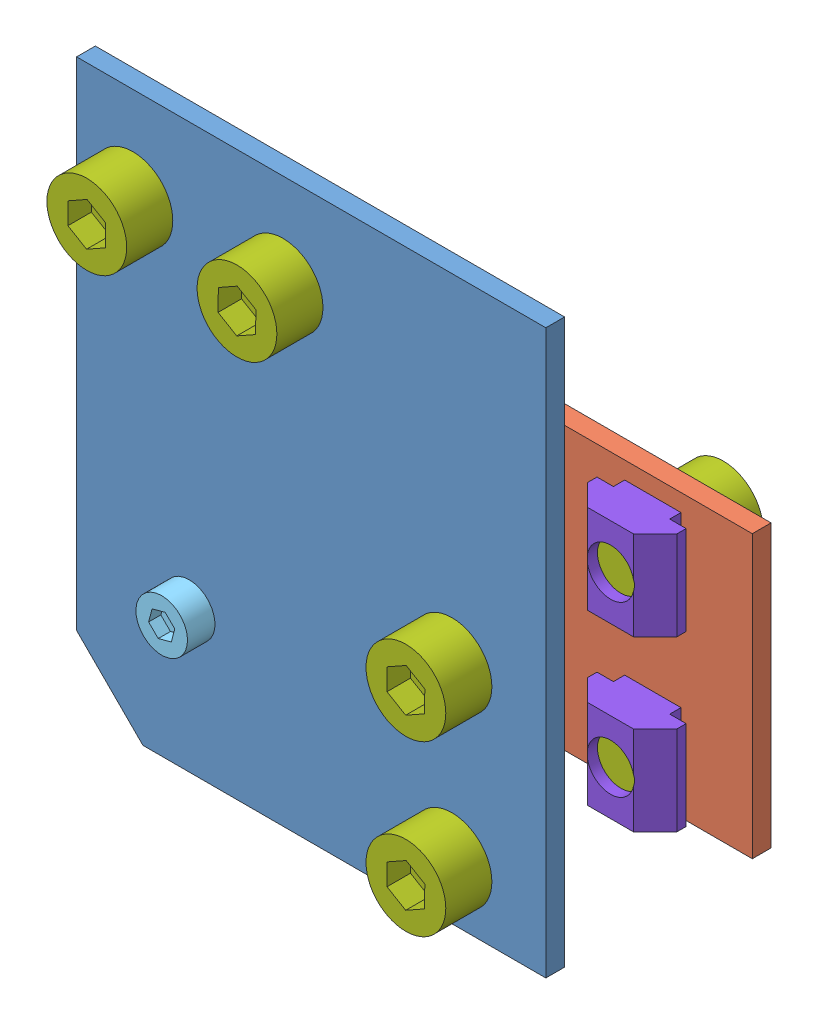
SolidWorks assembly 051XY惰轮组合1, configuration 默认. Lengths in mm.
Overall size (50 60 34.91).
21 component instances, 8 part files, 42 mates.
Components (placement in the parent):
- XY惰轮上固定片-1: XY惰轮上固定片 [默认] at (-52.8313 -43.6236 78.5) x (1 0 0) z (0 -1 0) size (50 2 60)
- XY惰轮下固定片-1: XY惰轮下固定片 [默认] at (-52.8313 -43.6236 56.5) x (1 0 0) z (0 -1 0) size (50 2 30)
- M3_6_1尼龙垫片-1: M3_6_1尼龙垫片 [默认] at (-40.8313 -28.6236 58.5) x (1 0 0) z (0 -1 0) size (6 1 6)
- 2GT惰轮6MM20齿3MM孔-带齿-1: 2GT惰轮6MM20齿3MM孔-带齿 [默认] at (-40.8313 -28.6236 59.5) x (1 0 0) z (0 -1 0) size (18 8.5 18)
- M3_6_1尼龙垫片-2: M3_6_1尼龙垫片 [默认] at (-40.8313 -28.6236 68) x (1 0 0) z (0 -1 0) size (6 1 6)
- 2GT惰轮6MM20齿3MM孔-带齿-2: 2GT惰轮6MM20齿3MM孔-带齿 [默认] at (-40.8313 -28.6236 69) x (1 0 0) z (0 -1 0) size (18 8.5 18)
- M3_6_1尼龙垫片-3: M3_6_1尼龙垫片 [默认] at (-40.8313 -28.6236 77.5) x (1 0 0) z (0 -1 0) size (6 1 6)
- M3_30-1: M3_30 [默认] at (-40.8313 -28.6236 50.5) x (1 0 0) z (0 -1 0) size (5.5 32.93 5.5)
- M3尼龙螺母-1: M3尼龙螺母 [默认] at (-40.8313 -28.6236 56.5) x (1 0 0) z (0 1 0) size (6.88 4 6.18)
- M5_6-1: M5_6 [默认] at (-12.8313 -37.6236 74.5) x (1 0 0) z (0 -1 0) size (8.5 10.91 8.5)
- M5_6-2: M5_6 [默认] at (-12.8313 -19.6236 74.5) x (1 0 0) z (0 -1 0) size (8.5 10.91 8.5)
- M5_6-3: M5_6 [默认] at (-46.8313 6.3764 74.5) x (1 0 0) z (0 -1 0) size (8.5 10.91 8.5)
- M5_6-4: M5_6 [默认] at (-30.8313 6.3764 74.5) x (1 0 0) z (0 -1 0) size (8.5 10.91 8.5)
- 欧标20M5滑块螺母-1: 欧标20M5滑块螺母 [默认] at (-51.5813 1.6264 73.4) x (1 0 0) z (0 -1 0) size (9.5 4.5 9.5)
- 欧标20M5滑块螺母-2: 欧标20M5滑块螺母 [默认] at (-35.5813 1.6264 73.4) x (1 0 0) z (0 -1 0) size (9.5 4.5 9.5)
- 欧标20M5滑块螺母-3: 欧标20M5滑块螺母 [默认] at (-8.0813 -24.3736 73.4) x (0 1 0) z (1 0 0) size (9.5 4.5 9.5)
- 欧标20M5滑块螺母-4: 欧标20M5滑块螺母 [默认] at (-8.0813 -42.3736 73.4) x (0 1 0) z (1 0 0) size (9.5 4.5 9.5)
- M5_6-5: M5_6 [默认] at (-12.8313 -19.6236 62.5) x (1 0 0) z (0 1 0) size (8.5 10.91 8.5)
- M5_6-6: M5_6 [默认] at (-12.8313 -37.6236 62.5) x (1 0 0) z (0 1 0) size (8.5 10.91 8.5)
- 欧标20M5滑块螺母-5: 欧标20M5滑块螺母 [默认] at (-17.5813 -24.3736 63.6) x (0 1 0) z (-1 0 0) size (9.5 4.5 9.5)
- 欧标20M5滑块螺母-6: 欧标20M5滑块螺母 [默认] at (-17.5813 -42.3736 63.6) x (0 1 0) z (-1 0 0) size (9.5 4.5 9.5)
Mates (geometry in assembly coordinates):
- 距离1: distance = 20 mm: plane of assembly; plane of assembly; plane of XY惰轮下固定片-1 through (-52.8313 -43.6236 58.5) normal (0 0 1); plane of XY惰轮上固定片-1 through (-52.8313 -43.6236 78.5) normal (0 0 -1)
- 同心2: concentric: circle of assembly; circle of assembly; circle of XY惰轮上固定片-1; circle of XY惰轮下固定片-1
- 重合1: coincident: plane of assembly; plane of assembly; plane of XY惰轮下固定片-1 through (-52.8313 -43.6236 58.5) normal (0 0 1); plane of M3_6_1尼龙垫片-1 through (-40.8313 -28.6236 58.5) normal (0 0 -1)
- 同心5: concentric: circle of assembly; circle of assembly; circle of XY惰轮下固定片-1; circle of M3_6_1尼龙垫片-1
- 重合2: coincident: plane of assembly; plane of assembly; plane of M3_6_1尼龙垫片-1 through (-40.8313 -28.6236 59.5) normal (0 0 1); plane of 2GT惰轮6MM20齿3MM孔-带齿-1 through (-40.8313 -28.6236 59.5) normal (0 0 -1)
- 同心6: concentric: circle of assembly; circle of assembly; circle of M3_6_1尼龙垫片-1; circle of 2GT惰轮6MM20齿3MM孔-带齿-1
- 重合3: coincident: plane of assembly; plane of assembly; plane of 2GT惰轮6MM20齿3MM孔-带齿-1 through (-40.8313 -28.6236 68) normal (0 0 1); plane of M3_6_1尼龙垫片-2 through (-40.8313 -28.6236 68) normal (0 0 -1)
- 同心7: concentric: circle of assembly; circle of assembly; circle of 2GT惰轮6MM20齿3MM孔-带齿-1; circle of M3_6_1尼龙垫片-2
- 重合4: coincident: plane of assembly; plane of assembly; plane of M3_6_1尼龙垫片-2 through (-40.8313 -28.6236 69) normal (0 0 1); plane of 2GT惰轮6MM20齿3MM孔-带齿-2 through (-40.8313 -28.6236 69) normal (0 0 -1)
- 同心8: concentric: circle of assembly; circle of assembly; circle of M3_6_1尼龙垫片-2; circle of 2GT惰轮6MM20齿3MM孔-带齿-2
- 重合5: coincident: plane of assembly; plane of assembly; plane of 2GT惰轮6MM20齿3MM孔-带齿-2 through (-40.8313 -28.6236 77.5) normal (0 0 1); plane of M3_6_1尼龙垫片-3 through (-40.8313 -28.6236 77.5) normal (0 0 -1)
- 同心9: concentric: circle of assembly; circle of assembly; circle of 2GT惰轮6MM20齿3MM孔-带齿-2; circle of M3_6_1尼龙垫片-3
- 同心10: concentric: cylinder of assembly; cylinder of assembly; cylinder of XY惰轮上固定片-1 through (-40.8313 -28.6236 78.5) axis (0 0 1) radius 1.75; cylinder of M3_30-1 through (-40.8313 -28.6236 80.5) axis (0 0 -1) radius 1.5
- 重合6: coincident: plane of assembly; plane of assembly; plane of XY惰轮上固定片-1 through (-52.8313 -43.6236 80.5) normal (0 0 1); plane of M3_30-1 through (-40.8313 -28.6236 80.5) normal (0 0 -1)
- 同心11: concentric: cylinder of assembly; cylinder of assembly; cylinder of M3_30-1 through (-40.8313 -28.6236 80.5) axis (0 0 -1) radius 1.5; cylinder of M3尼龙螺母-1 through (-40.8313 -28.6236 52.5) axis (0 0 1) radius 1.5
- 重合7: coincident: plane of assembly; plane of assembly; plane of XY惰轮下固定片-1 through (-52.8313 -43.6236 56.5) normal (0 0 -1); plane of M3尼龙螺母-1 through (-40.8313 -28.6236 56.5) normal (0 0 1)
- 重合8: coincident: plane of assembly; plane of assembly; plane of XY惰轮上固定片-1 through (-52.8313 -43.6236 80.5) normal (0 0 1); plane of M5_6-3 through (-46.8313 6.3764 80.5) normal (0 0 -1)
- 同心12: concentric: cylinder of assembly; cylinder of assembly; cylinder of XY惰轮上固定片-1 through (-46.8313 6.3764 78.5) axis (0 0 1) radius 2.75; cylinder of M5_6-3 through (-46.8313 6.3764 80.5) axis (0 0 -1) radius 2.5
- 同心13: concentric: cylinder of assembly; cylinder of assembly; cylinder of M5_6-3 through (-46.8313 6.3764 80.5) axis (0 0 -1) radius 2.5; cylinder of 欧标20M5滑块螺母-1 through (-46.8313 6.3764 73.4) axis (0 0 1) radius 2.5
- 距离2: distance = 1.8 mm: plane of assembly; plane of assembly; plane of XY惰轮上固定片-1 through (-52.8313 -43.6236 78.5) normal (0 0 -1); plane of 欧标20M5滑块螺母-1 through (-51.5813 1.6264 76.7) normal (0 0 1)
- 重合9: coincident: plane of assembly; plane of assembly; plane of XY惰轮上固定片-1 through (-52.8313 -43.6236 80.5) normal (0 0 1); plane of M5_6-4 through (-30.8313 6.3764 80.5) normal (0 0 -1)
- 同心14: concentric: cylinder of assembly; cylinder of assembly; cylinder of XY惰轮上固定片-1 through (-30.8313 6.3764 78.5) axis (0 0 1) radius 2.75; cylinder of M5_6-4 through (-30.8313 6.3764 80.5) axis (0 0 -1) radius 2.5
- 同心15: concentric: cylinder of assembly; cylinder of assembly; cylinder of M5_6-4 through (-30.8313 6.3764 80.5) axis (0 0 -1) radius 2.5; cylinder of 欧标20M5滑块螺母-2 through (-30.8313 6.3764 73.4) axis (0 0 1) radius 2.5
- 距离3: distance = 1.8 mm: plane of assembly; plane of assembly; plane of XY惰轮上固定片-1 through (-52.8313 -43.6236 78.5) normal (0 0 -1); plane of 欧标20M5滑块螺母-2 through (-35.5813 1.6264 76.7) normal (0 0 1)
- 重合10: coincident: plane of assembly; plane of assembly; plane of XY惰轮上固定片-1 through (-52.8313 -43.6236 80.5) normal (0 0 1); plane of M5_6-2 through (-12.8313 -19.6236 80.5) normal (0 0 -1)
- 同心16: concentric: cylinder of assembly; cylinder of assembly; cylinder of XY惰轮上固定片-1 through (-12.8313 -19.6236 78.5) axis (0 0 1) radius 2.75; cylinder of M5_6-2 through (-12.8313 -19.6236 80.5) axis (0 0 -1) radius 2.5
- 同心17: concentric: cylinder of assembly; cylinder of assembly; cylinder of M5_6-2 through (-12.8313 -19.6236 80.5) axis (0 0 -1) radius 2.5; cylinder of 欧标20M5滑块螺母-3 through (-12.8313 -19.6236 73.4) axis (0 0 1) radius 2.5
- 距离4: distance = 1.8 mm: plane of XY惰轮上固定片-1 through (-52.8313 -43.6236 78.5) normal (0 0 -1); plane of 欧标20M5滑块螺母-3 through (-8.0813 -24.3736 76.7) normal (0 0 1)
- 平行1: parallel: plane of XY惰轮上固定片-1 through (-2.8313 -43.6236 80.5) normal (1 0 0); plane of 欧标20M5滑块螺母-3 through (-17.5813 -14.8736 76.7) normal (-1 0 0)
- 重合11: coincident: plane of assembly; plane of assembly; plane of XY惰轮上固定片-1 through (-52.8313 -43.6236 80.5) normal (0 0 1); plane of M5_6-1 through (-12.8313 -37.6236 80.5) normal (0 0 -1)
- 同心18: concentric: cylinder of XY惰轮上固定片-1 through (-12.8313 -37.6236 78.5) axis (0 0 1) radius 2.75; cylinder of M5_6-1 through (-12.8313 -37.6236 80.5) axis (0 0 -1) radius 2.5
- 同心19: concentric: cylinder of M5_6-1 through (-12.8313 -37.6236 80.5) axis (0 0 -1) radius 2.5; cylinder of 欧标20M5滑块螺母-4 through (-12.8313 -37.6236 73.4) axis (0 0 1) radius 2.5
- 距离5: distance = 1.8 mm: plane of XY惰轮上固定片-1 through (-52.8313 -43.6236 78.5) normal (0 0 -1); plane of 欧标20M5滑块螺母-4 through (-8.0813 -42.3736 76.7) normal (0 0 1)
- 平行2: parallel: plane of XY惰轮上固定片-1 through (-2.8313 -43.6236 80.5) normal (1 0 0); plane of 欧标20M5滑块螺母-4 through (-17.5813 -32.8736 76.7) normal (-1 0 0)
- 重合12: coincident: plane of assembly; plane of assembly; plane of XY惰轮下固定片-1 through (-52.8313 -43.6236 56.5) normal (0 0 -1); plane of M5_6-5 through (-12.8313 -19.6236 56.5) normal (0 0 1)
- 重合13: coincident: plane of assembly; plane of assembly; plane of XY惰轮下固定片-1 through (-52.8313 -43.6236 56.5) normal (0 0 -1); plane of M5_6-6 through (-12.8313 -37.6236 56.5) normal (0 0 1)
- 同心20: concentric: cylinder of XY惰轮下固定片-1 through (-12.8313 -19.6236 56.5) axis (0 0 1) radius 2.75; cylinder of M5_6-5 through (-12.8313 -19.6236 56.5) axis (0 0 1) radius 2.5
- 同心21: concentric: cylinder of XY惰轮下固定片-1 through (-12.8313 -37.6236 56.5) axis (0 0 1) radius 2.75; cylinder of M5_6-6 through (-12.8313 -37.6236 56.5) axis (0 0 1) radius 2.5
- 同心22: concentric: cylinder of M5_6-5 through (-12.8313 -19.6236 56.5) axis (0 0 1) radius 2.5; cylinder of 欧标20M5滑块螺母-5 through (-12.8313 -19.6236 63.6) axis (0 0 -1) radius 2.5
- 同心23: concentric: cylinder of M5_6-6 through (-12.8313 -37.6236 56.5) axis (0 0 1) radius 2.5; cylinder of 欧标20M5滑块螺母-6 through (-12.8313 -37.6236 63.6) axis (0 0 -1) radius 2.5
- 距离6: distance = 1.8 mm: plane of 欧标20M5滑块螺母-5 through (-17.5813 -24.3736 60.3) normal (0 0 -1); plane of XY惰轮下固定片-1 through (-52.8313 -43.6236 58.5) normal (0 0 1)
- 距离7: distance = 1.8 mm: plane of assembly; plane of assembly; plane of XY惰轮下固定片-1 through (-52.8313 -43.6236 58.5) normal (0 0 1); plane of 欧标20M5滑块螺母-6 through (-17.5813 -42.3736 60.3) normal (0 0 -1)
